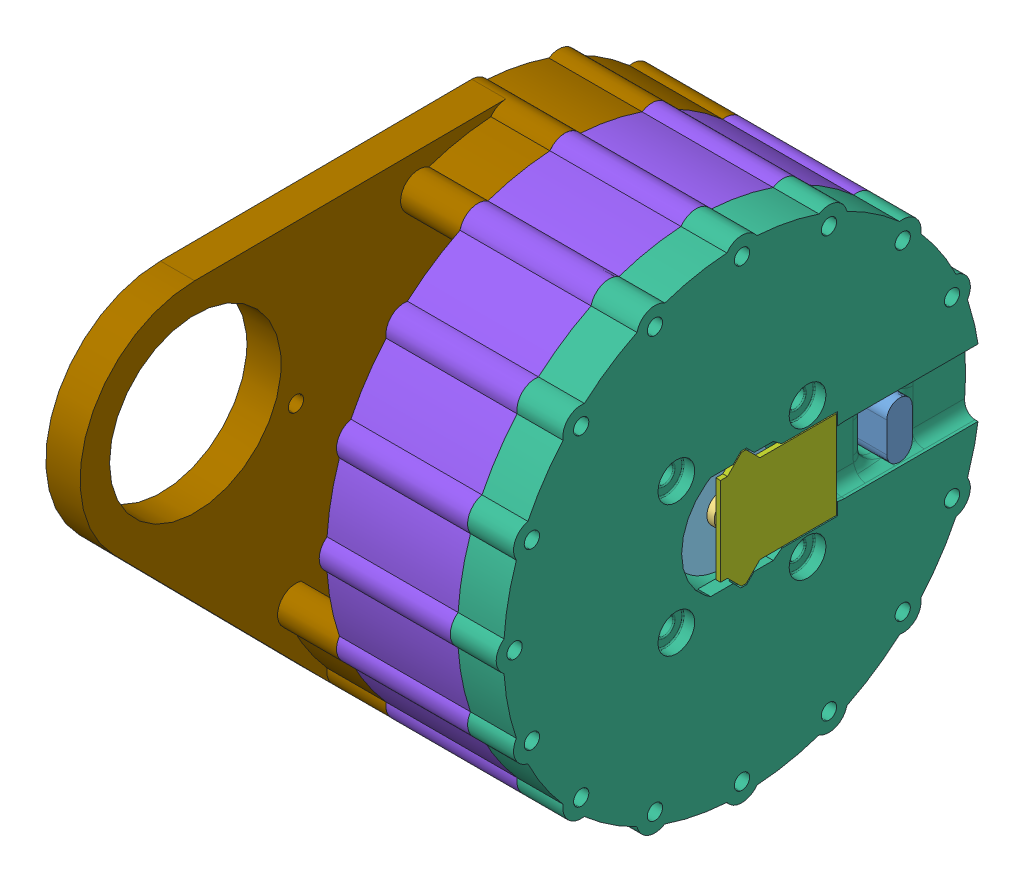
SolidWorks assembly outrigged support plate, configuration Default. Lengths in mm.
Overall size (190.93 129.63 496.75).
11 component instances, 10 part files, 6 mates.
Components (placement in the parent):
- 0 Dimensions-1: 0 Dimensions [Default] at origin size (152.4 91.19 482.73)
- Motor Assem-1: Motor Assem [Default] at (14.125 0 0) x (0 1 0) z (0 0 1) size (129.63 57.83 129.63)
  - 9225 160kv-1: 9225 160kv [Default] at (0 -18.055 0) x (0.707107 0 0.707107) z (-0.707107 0 0.707107) size (91.66 44.53 91.66)
  - 15 tooth htd 3mm pulley-1: 15 tooth htd 3mm pulley [Default] at (0 21.7525 0) x (0.707107 0 0.707107) z (-0.707107 0 0.707107) size (39.69 19.3 39.69)
  - Encoder Magnet-1: Encoder Magnet [Default] at (0 -19.6425 0) size (6.35 3.17 6.35)
  - Bearing 15_24_5mm-1: Bearing 15_24_5mm [Default] at (0 30.9275 0) size (24 5 24)
  - Magnut hex puck-1: Magnut hex puck [Default] at (0 -18.055 0) x (0.707107 0 0.707107) z (-0.707107 0 0.707107) size (22.91 4.76 22.91)
  - Motor Bracket Base-1: Motor Bracket Base [Default] at origin size (105.95 14.23 104.36)
  - encoder final board-1: encoder final board [Default] at (0 -23.0237 -0.3766) x (0 0 -1) z (1 0 0) size (25.25 2.95 25)
  - Part1-1: Part1 [Default] at origin size (105.95 28.25 104.36)
- outrigger_pulley_support-1: outrigger_pulley_support [Default] x (0 0 -1) z (-1 0 0) size (143.19 105.95 20.1)
Mates (geometry in assembly coordinates):
- Coincident1: coincident aligned: line of 0 Dimensions-1 through (0 50.8 -152.4) axis (0 0 1); line of Motor Assem-1 through (-22.1941 0 0) axis (1 0 0)
- Coincident2: coincident aligned: plane of Motor Assem-1 through (14.125 0 0) normal (0 1 0)
- Coincident3: coincident anti-aligned: plane of 0 Dimensions-1 through (0 0 0) normal (1 0 0); plane of Motor Assem-1/Part1-1 through (0 22.981 22.981) normal (-1 0 0)
- Coincident8: coincident aligned: plane of Motor Assem-1/Part1-1 through (0 22.981 22.981) normal (-1 0 0); plane of Part4^outrigged support plate-1 through (0 0 0) normal (-1 0 0)
- Coincident9: coincident anti-aligned: plane of Part4^outrigged support plate-1 through (0 0 0) normal (0 -1 0)
- Coincident10: coincident: point of 0 Dimensions-1; plane of Part4^outrigged support plate-1 through (0 0 0) normal (0 0 -1)
